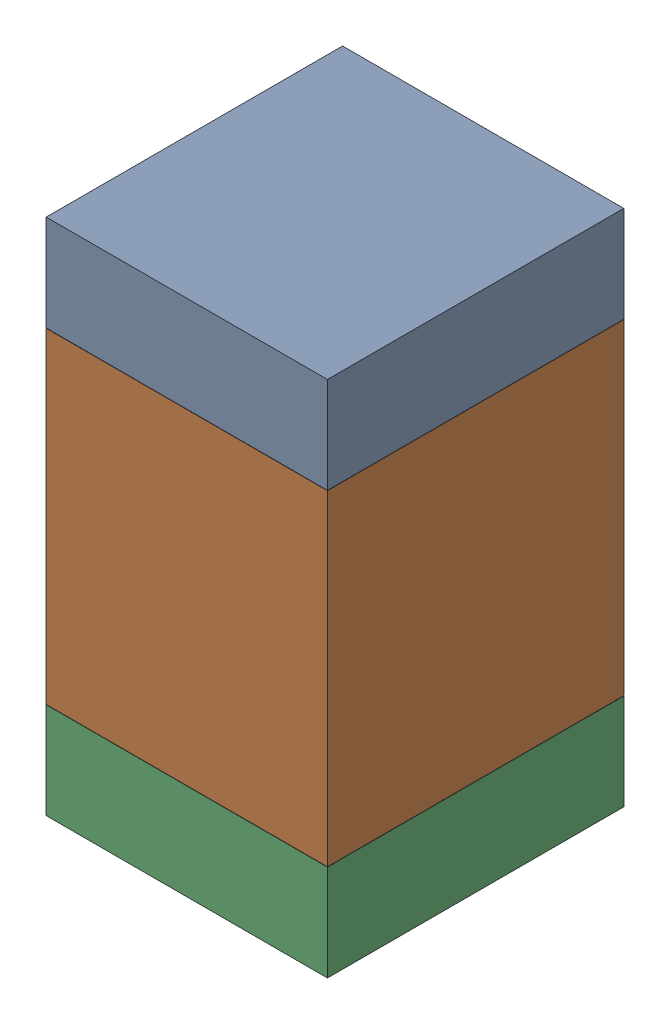
SolidWorks assembly C2, configuration Default. Lengths in mm.
Overall size (0.95 1.75 1).
6 component instances, 2 part files, 0 mates.
Components (placement in the parent):
- 6575495072-1: 6575495072 [Default] at (22.098 41.3525 0) size (0.95 0.32 1)
  - Extruded_6-1: Extruded_6 [Default] at origin size (0.95 0.32 1)
- 6575494912-1: 6575494912 [Default] at (22.098 40.64 0) size (0.95 1.1 1)
  - Extruded_7-1: Extruded_7 [Default] at origin size (0.95 1.1 1)
- 6575495072-2: 6575495072 [Default] at (22.098 39.9275 0) size (0.95 0.32 1)
  - Extruded_6-1: Extruded_6 [Default] at origin size (0.95 0.32 1)
